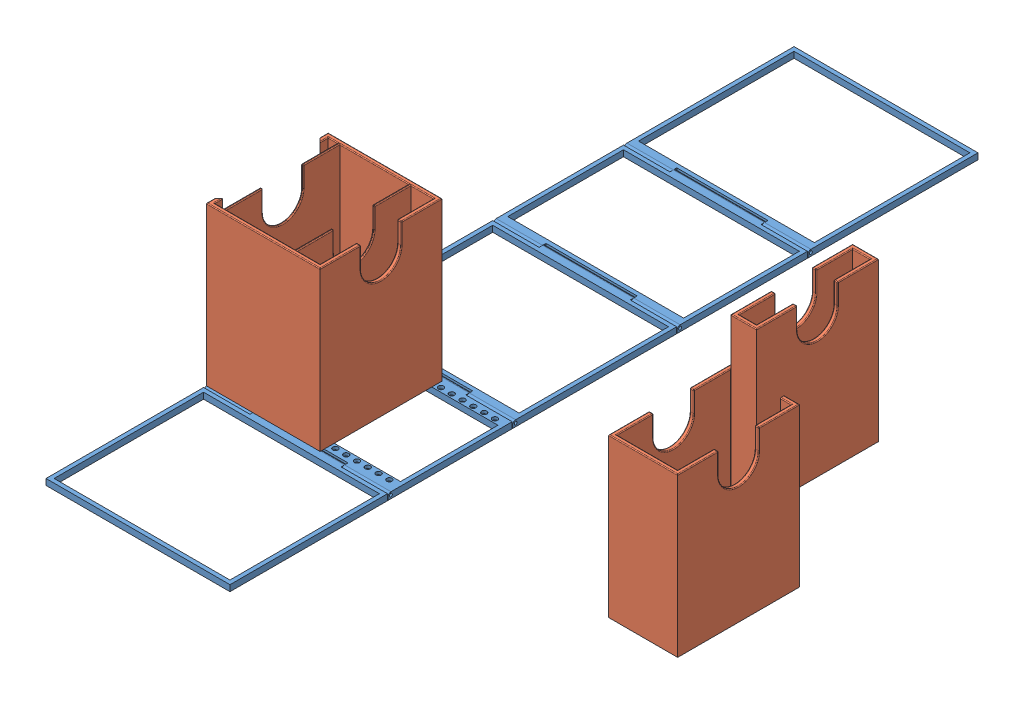
SolidWorks assembly Box and Carrier Assembly, configuration Default. Lengths in mm.
Overall size (248.5 145.04 467.87).
10 component instances, 3 part files, 15 mates.
Components (placement in the parent):
- Cover-1: Cover [B] at (21.5647 62.4046 94.6513) size (115.06 3.81 81.79)
- DeckBase-1: DeckBase [CompleteDeckA] at (-92.1608 68.7546 94.9307) x (0 0 -1) z (1 0 0) size (76.2 99.06 71.12)
- DeckBase-2: DeckBase [SizeA] at (314.4357 67.4366 -32.5068) x (0 0 1) z (-1 0 0) size (76.2 99.06 16.08)
- DeckBase-3: DeckBase [SizeB] at (323.8634 22.7738 26.2668) x (0 0 1) z (-1 0 0) size (76.2 99.06 43.18)
- Magnet 3x2mm-1: Magnet 3x2mm [Default] at (59.1669 64.4366 115.4768) size (3 2 3)
- Magnet 3x2mm-2: Magnet 3x2mm [Default] at (45.7811 64.6906 115.4768) x (0.837169 0 0.546944) z (0.546944 0 -0.837169) size (3 2 3)
- Cover-2: Cover [A] at (21.5647 62.4046 197.5213) size (115.06 3.81 102.62)
- Cover-3: Cover [C] at (21.5647 62.4046 16.6733) size (115.06 3.81 106.68)
- Cover-4: Cover [D] at (21.5647 62.4046 -86.1967) size (115.06 3.81 85.6)
- Cover-5: Cover [E] at (21.5647 62.4046 -167.9847) size (115.06 3.81 106.43)
Mates (geometry in assembly coordinates):
- Concentric3: concentric aligned: cylinder of Cover-1 through (109.6387 64.3096 121.4458) axis (-1 0 0) radius 0.889; cylinder of Cover-2 through (109.6387 64.3096 121.4458) axis (-1 0 0) radius 0.889
- Coincident14: coincident aligned: plane of Cover-1 through (-8.3971 66.2146 94.6513) normal (-1 0 0); plane of Cover-2 through (-8.3971 66.2146 197.5213) normal (-1 0 0)
- Concentric4: concentric aligned: cylinder of Cover-1 through (109.6387 64.3096 43.4678) axis (-1 0 0) radius 0.889; cylinder of Cover-3 through (109.6387 64.3096 43.4678) axis (-1 0 0) radius 0.889
- Coincident15: coincident aligned: plane of Cover-1 through (-8.3971 66.2146 94.6513) normal (-1 0 0); plane of Cover-3 through (-8.3971 66.2146 16.6733) normal (-1 0 0)
- Concentric5: concentric aligned: cylinder of Cover-3 through (109.6387 64.3096 -59.4022) axis (-1 0 0) radius 0.889; cylinder of Cover-4 through (109.6387 64.3096 -59.4022) axis (-1 0 0) radius 0.889
- Coincident16: coincident aligned: plane of Cover-3 through (-8.3971 66.2146 16.6733) normal (-1 0 0); plane of Cover-4 through (-8.3971 66.2146 -86.1967) normal (-1 0 0)
- Concentric6: concentric aligned: cylinder of Cover-4 through (109.6387 64.3096 -141.1902) axis (-1 0 0) radius 0.889; cylinder of Cover-5 through (109.6387 64.3096 -141.1902) axis (-1 0 0) radius 0.889
- Coincident17: coincident aligned: plane of Cover-4 through (-8.3971 66.2146 -86.1967) normal (-1 0 0); plane of Cover-5 through (-8.3971 66.2146 -167.9847) normal (-1 0 0)
- Coincident18: coincident anti-aligned: plane of Cover-1 through (21.5647 66.2146 94.6513) normal (0 1 0); plane of DeckBase-1 through (-92.1608 66.2146 94.9307) normal (0 -1 0)
- Coincident19: coincident aligned: plane of Cover-1 through (-8.3971 66.2146 94.6513) normal (-1 0 0); plane of DeckBase-1 through (-8.3971 165.2746 94.9307) normal (-1 0 0)
- Coincident20: coincident aligned: plane of Cover-1 through (21.5647 5.237 45.6268) normal (0 0 -1); plane of DeckBase-1 through (-92.1608 165.2746 45.6268) normal (0 0 -1)
- LimitAngle2: limit planar angle = 3.141593 rad anti-aligned: plane of Cover-1 through (21.5647 66.2146 94.6513) normal (0 1 0); plane of Cover-2 through (21.5647 66.2146 197.5213) normal (0 1 0)
- LimitAngle4: limit planar angle = 0 rad aligned: plane of Cover-3 through (21.5647 66.2146 16.6733) normal (0 1 0); plane of Cover-1 through (21.5647 66.2146 94.6513) normal (0 1 0)
- LimitAngle5: limit planar angle = 3.141593 rad anti-aligned: plane of Cover-4 through (21.5647 66.2146 -86.1967) normal (0 1 0); plane of Cover-3 through (21.5647 66.2146 16.6733) normal (0 1 0)
- LimitAngle6: limit planar angle = 3.141593 rad anti-aligned: plane of Cover-5 through (21.5647 66.2146 -167.9847) normal (0 1 0); plane of Cover-4 through (21.5647 66.2146 -86.1967) normal (0 1 0)
